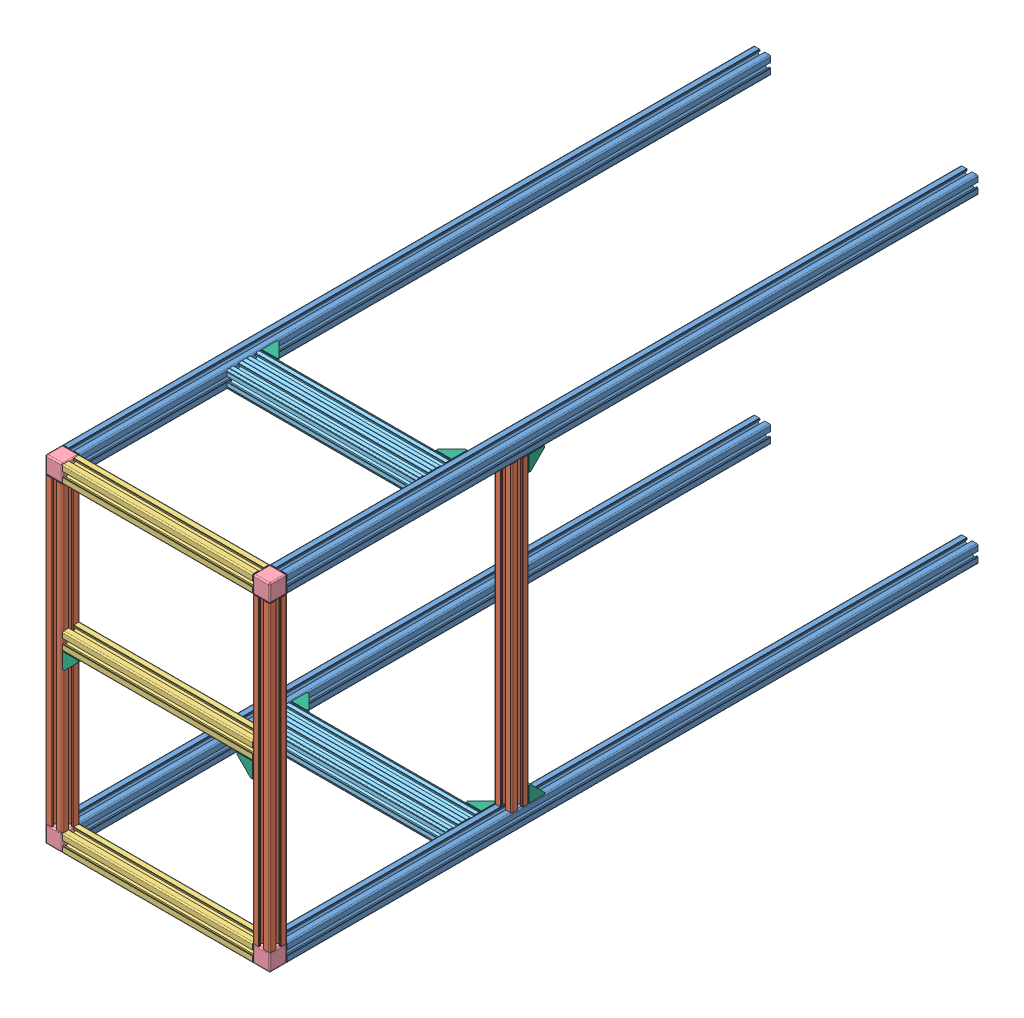
SolidWorks assembly Assemblage bati profilé dague, configuration Défaut. Lengths in mm.
Overall size (520 780 1640).
25 component instances, 6 part files, 0 mates.
Components (placement in the parent):
- bati partie haute-1: bati partie haute [Défaut] at (-15.1406 304.6621 -267.4151) x (0 1 0) z (0 0 -1) size (780 520 1640)
  - 1636 mm-1: 1636 mm [Défaut] at (-690.2499 -110.2045 843.4804) size (40 40 1600)
  - 1636 mm-2: 1636 mm [Défaut] at (49.7501 -110.2045 843.4804) x (0 1 0) z (0 0 1) size (40 40 1600)
  - 1636 mm-3: 1636 mm [Défaut] at (49.7501 369.7955 843.4804) x (0 -1 0) z (0 0 1) size (40 40 1600)
  - 1636 mm-4: 1636 mm [Défaut] at (-690.2499 369.7955 843.4804) size (40 40 1600)
  - 700 mm-1: 700 mm [Défaut] at (-570.2499 369.7955 -676.5196) x (0 0 1) z (-1 0 0) size (40 40 700)
  - 700 mm-2: 700 mm [Défaut] at (-70.2499 -110.2045 -676.5196) x (0 0 -1) z (1 0 0) size (40 40 700)
  - 440 mm-1: 440 mm [Défaut] at (49.7501 249.7955 -676.5196) x (1 0 0) z (0 1 0) size (40 40 440)
  - 440 mm-2: 440 mm [Défaut] at (-690.2499 249.7955 -676.5196) x (1 0 0) z (0 1 0) size (40 40 440)
  - cache 40 40 40-1: cache 40 40 40 [Défaut] at (-708.8962 368.9411 -656.5196) x (-1 0 0) z (0 0 -1) size (40 40 40)
  - cache 40 40 40-2: cache 40 40 40 [Défaut] at (-671.6035 -109.35 -656.5196) x (1 0 0) z (0 0 -1) size (40 40 40)
  - cache 40 40 40-3: cache 40 40 40 [Défaut] at (48.8957 388.4419 -656.5196) x (0 1 0) z (0 0 -1) size (40 40 40)
  - cache 40 40 40-4: cache 40 40 40 [Défaut] at (68.3965 -109.35 -656.5196) x (1 0 0) z (0 0 -1) size (40 40 40)
  - 440-1: 440 [Défaut] at (49.7501 249.7955 -275.4151) x (1 0 0) z (0 1 0) size (40 80 440)
  - 440-2: 440 [Défaut] at (-690.2499 249.7955 -206.5196) x (1 0 0) z (0 1 0) size (40 80 440)
  - 700 mm-3: 700 mm [Défaut] at (-70.2499 369.7955 -116.5196) x (0 0 -1) z (1 0 0) size (40 40 700)
  - 440 mm-4: 440 mm [Défaut] at (-285.2499 249.7955 -676.5196) x (1 0 0) z (0 1 0) size (40 40 440)
  - equerre 40x40-1: equerre 40x40 [Défaut] at (-670.2499 370.7955 -96.5196) x (0 1 0) z (0 0 1) size (38 36 36)
  - equerre 40x40-2: equerre 40x40 [Défaut] at (-689.2499 -90.2045 -166.5196) x (1 0 0) z (0 1 0) size (38 36 36)
  - equerre 40x40-3: equerre 40x40 [Défaut] at (50.7501 349.7955 -235.4151) size (38 36 36)
  - equerre 40x40-4: equerre 40x40 [Défaut] at (-305.2499 349.7955 -677.5196) x (0 0 -1) z (0 -1 0) size (38 36 36)
  - equerre 40x40-5: equerre 40x40 [Défaut] at (-689.2499 349.7955 -166.5196) size (38 36 36)
  - equerre 40x40-6: equerre 40x40 [Défaut] at (-305.2499 -90.2045 -677.5196) x (0 0 1) z (0 1 0) size (38 36 36)
  - equerre 40x40-7: equerre 40x40 [Défaut] at (29.7501 370.7955 -96.5196) x (0 -1 0) z (0 0 1) size (38 36 36)
  - equerre 40x40-8: equerre 40x40 [Défaut] at (50.7501 -90.2045 -235.4151) x (-1 0 0) z (0 0 1) size (38 36 36)
